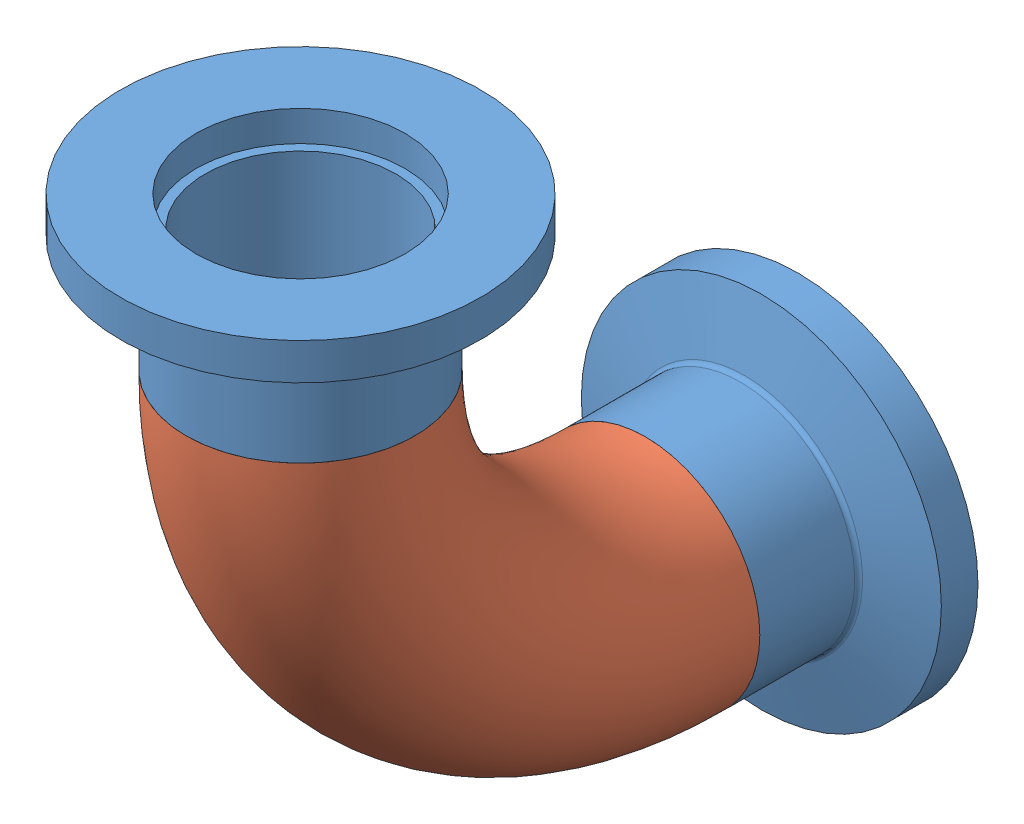
SolidWorks assembly 723000, configuration Default. Lengths in mm.
Overall size (34.22 56.39 58.51).
3 component instances, 2 part files, 3 mates.
Components (placement in the parent):
- 713001-1: 713001 [Default] at (14.9456 10.6922 19.1621) size (29.97 29.97 14.22)
- 403500-1: 403500 [Default] at (14.9456 10.6922 31.8621) size (19.05 38.23 38.23)
- 713001-2: 713001 [Default] at (14.9456 52.0942 60.5641) x (-0.15374 0 -0.988111) z (0 -1 0) size (29.97 29.97 14.22)
Mates (geometry in assembly coordinates):
- Coincident1: coincident anti-aligned: circle of 713001-REV.E-1; circle of 403500-REV.A-1
- Parallel1: parallel aligned: plane of 403500-REV.A-1 through (14.9456 10.6922 31.8621) normal (1 0 0)
- Coincident3: coincident aligned: circle of 403500-REV.A-1; circle of 713001-REV.E-2
